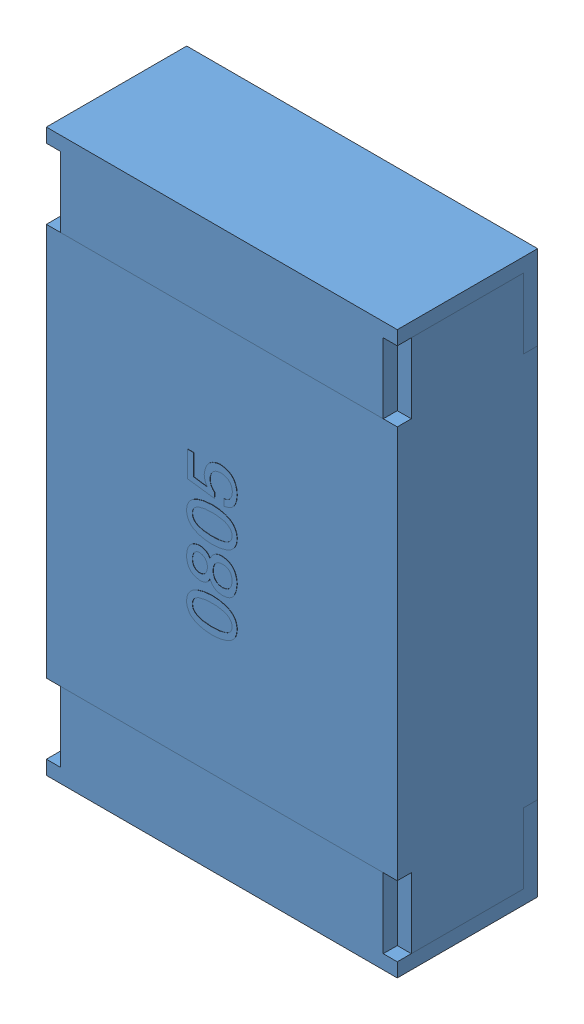
SolidWorks assembly 0805电阻, configuration 默认. Lengths in mm.
Overall size (1.25 2 0.5).
2 component instances, 1 part files, 0 mates.
Components (placement in the parent):
- R_0805^0805电阻-1: R_0805^0805电阻 [默认] at (112.776 107.442 0) x (0 1 0) z (0 0 1) size (2 1.25 0.5) (virtual)
  - R_0805-21^R_0805_0805电阻-1: R_0805-21^R_0805_0805电阻 [默认] at origin size (2 1.25 0.5) (virtual)
